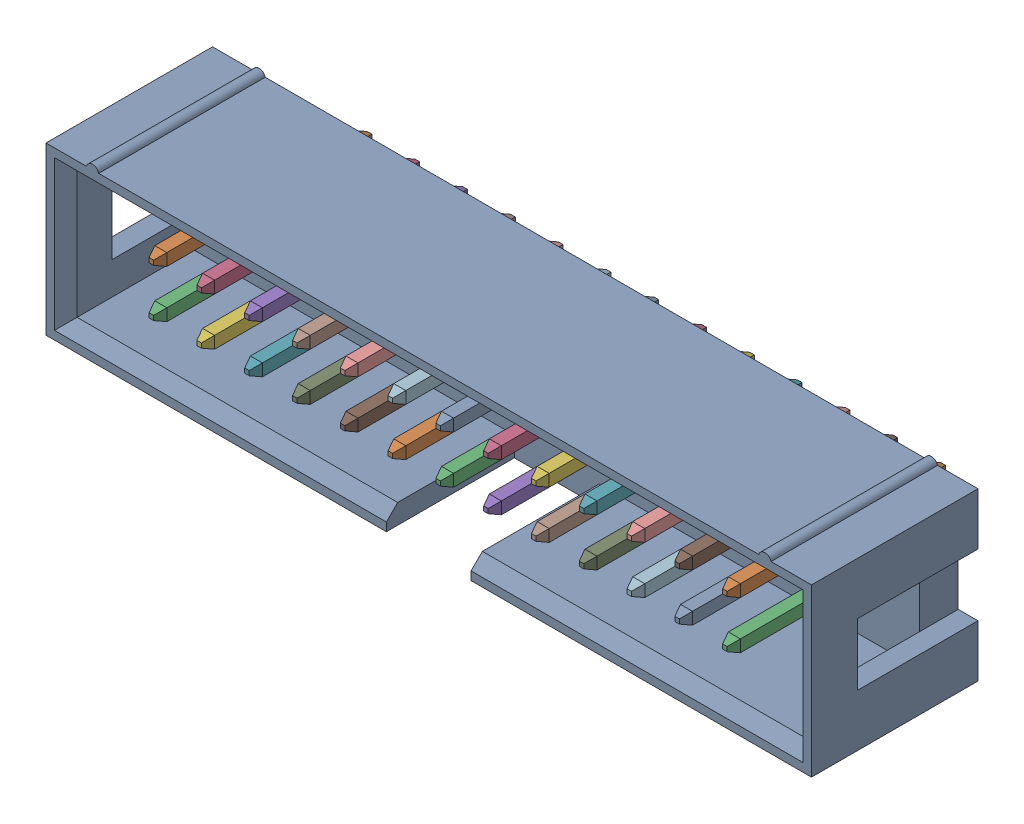
SolidWorks assembly J3, configuration Default. Lengths in mm.
Overall size (40.68 9.1 12.1).
28 component instances, 2 part files, 0 mates.
Components (placement in the parent):
- STEP-61202621621-rev1-1: STEP-61202621621-rev1 [Default] at (135.2551 70.2531 4.4377) x (1 0 0) z (0 0 1) size (40.68 9.1 12.1)
  - 61202621621-1: 61202621621 [Default] at origin size (40.68 9.1 9.1)
  - 6120xx21621_PIN-1: 6120xx21621_PIN [Default] at (-15.24 1.27 -1.875) size (0.64 0.64 11.6)
  - 6120xx21621_PIN-2: 6120xx21621_PIN [Default] at (-15.24 -1.27 -1.875) size (0.64 0.64 11.6)
  - 6120xx21621_PIN-3: 6120xx21621_PIN [Default] at (-12.7 1.27 -1.875) size (0.64 0.64 11.6)
  - 6120xx21621_PIN-4: 6120xx21621_PIN [Default] at (-10.16 1.27 -1.875) size (0.64 0.64 11.6)
  - 6120xx21621_PIN-5: 6120xx21621_PIN [Default] at (-12.7 -1.27 -1.875) size (0.64 0.64 11.6)
  - 6120xx21621_PIN-6: 6120xx21621_PIN [Default] at (-10.16 -1.27 -1.875) size (0.64 0.64 11.6)
  - 6120xx21621_PIN-7: 6120xx21621_PIN [Default] at (-7.62 1.27 -1.875) size (0.64 0.64 11.6)
  - 6120xx21621_PIN-8: 6120xx21621_PIN [Default] at (-7.62 -1.27 -1.875) size (0.64 0.64 11.6)
  - 6120xx21621_PIN-9: 6120xx21621_PIN [Default] at (-5.08 1.27 -1.875) size (0.64 0.64 11.6)
  - 6120xx21621_PIN-10: 6120xx21621_PIN [Default] at (-5.08 -1.27 -1.875) size (0.64 0.64 11.6)
  - 6120xx21621_PIN-11: 6120xx21621_PIN [Default] at (-2.54 1.27 -1.875) size (0.64 0.64 11.6)
  - 6120xx21621_PIN-12: 6120xx21621_PIN [Default] at (0 1.27 -1.875) size (0.64 0.64 11.6)
  - 6120xx21621_PIN-13: 6120xx21621_PIN [Default] at (-2.54 -1.27 -1.875) size (0.64 0.64 11.6)
  - 6120xx21621_PIN-14: 6120xx21621_PIN [Default] at (0 -1.27 -1.875) size (0.64 0.64 11.6)
  - 6120xx21621_PIN-15: 6120xx21621_PIN [Default] at (2.54 1.27 -1.875) size (0.64 0.64 11.6)
  - 6120xx21621_PIN-16: 6120xx21621_PIN [Default] at (2.54 -1.27 -1.875) size (0.64 0.64 11.6)
  - 6120xx21621_PIN-17: 6120xx21621_PIN [Default] at (5.08 1.27 -1.875) size (0.64 0.64 11.6)
  - 6120xx21621_PIN-18: 6120xx21621_PIN [Default] at (7.62 1.27 -1.875) size (0.64 0.64 11.6)
  - 6120xx21621_PIN-19: 6120xx21621_PIN [Default] at (5.08 -1.27 -1.875) size (0.64 0.64 11.6)
  - 6120xx21621_PIN-20: 6120xx21621_PIN [Default] at (7.62 -1.27 -1.875) size (0.64 0.64 11.6)
  - 6120xx21621_PIN-21: 6120xx21621_PIN [Default] at (10.16 1.27 -1.875) size (0.64 0.64 11.6)
  - 6120xx21621_PIN-22: 6120xx21621_PIN [Default] at (12.7 1.27 -1.875) size (0.64 0.64 11.6)
  - 6120xx21621_PIN-23: 6120xx21621_PIN [Default] at (10.16 -1.27 -1.875) size (0.64 0.64 11.6)
  - 6120xx21621_PIN-24: 6120xx21621_PIN [Default] at (12.7 -1.27 -1.875) size (0.64 0.64 11.6)
  - 6120xx21621_PIN-25: 6120xx21621_PIN [Default] at (15.24 1.27 -1.875) size (0.64 0.64 11.6)
  - 6120xx21621_PIN-26: 6120xx21621_PIN [Default] at (15.24 -1.27 -1.875) size (0.64 0.64 11.6)
